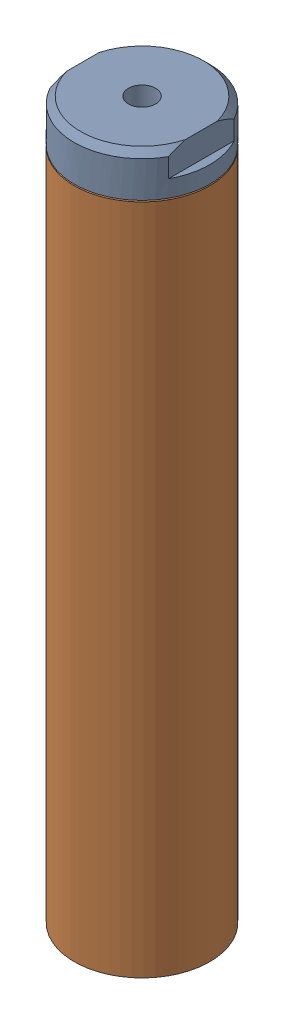
SolidWorks assembly BLB-ASM10, configuration Default. Lengths in mm.
Overall size (25.4 134.16 25.4).
3 component instances, 3 part files, 0 mates.
Components (placement in the parent):
- BS-18-33R-1: BS-18-33R [Default] at origin size (25.4 12.7 25.4)
- BT-33R-SM-1: BT-33R-SM [Default] at (0 -121.4628 0) size (25.4 126.21 25.4)
- RNG18COP-1: RNG18COP [Default] at (0 -0.5842 0) size (24.13 1.07 24.12)
